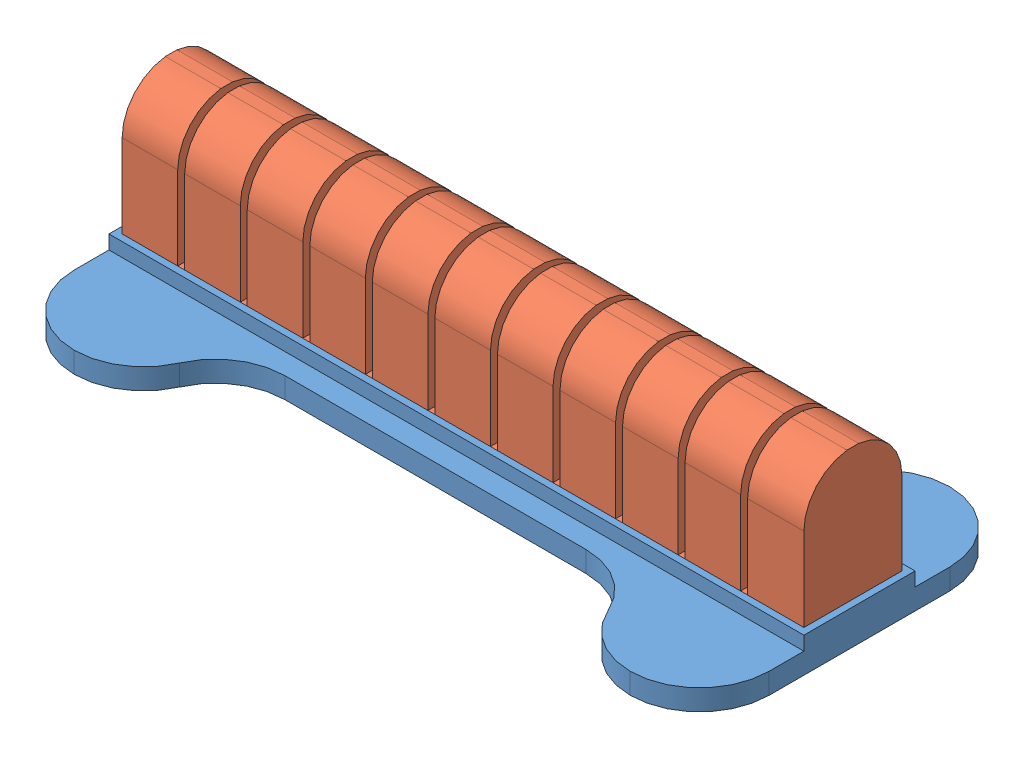
SolidWorks assembly Assem_nov4, configuration Default. Lengths in mm.
Overall size (100 24 46).
3 component instances, 3 part files, 6 mates.
Components (placement in the parent):
- SR_nov4_Male-1: SR_nov4_Male [Default] at (-87.585 -18.8498 34.1852) size (100 19 46)
- FInger_actuator_nov4-1: FInger_actuator_nov4 [Default] at (-87.585 -13.8498 18.1852) size (98.1 22 14.1)
- SR_Oct31_female-1: SR_Oct31_female [Default] at (187.4738 6.1502 -77.3442) x (1 0 0) z (0 0 -1) size (104 22 46) (hidden)
Mates (geometry in assembly coordinates):
- Coincident1: coincident: plane of SR_nov4_Male-1 through (-87.585 -13.8498 34.1852) normal (0 1 0); plane of FInger_actuator_nov4-1 through (-87.585 -13.8498 18.1852) normal (0 -1 0)
- Coincident2: coincident: plane of SR_nov4_Male-1 through (-87.585 -15.8498 34.1852) normal (-1 0 0); plane of FInger_actuator_nov4-1 through (-87.585 5.1502 18.1852) normal (-1 0 0)
- Coincident3: coincident: plane of SR_nov4_Male-1 through (-87.585 -12.8498 34.1852) normal (0 0 1); plane of FInger_actuator_nov4-1 through (-87.585 5.1502 34.1852) normal (0 0 1)
- Coincident9: coincident: plane of SR_nov4_Male-1 through (-87.585 -15.8498 34.1852) normal (-1 0 0); plane of SR_Oct31_female-1 through (-87.585 -13.8498 34.1852) normal (-1 0 0)
- Coincident10: coincident: plane of SR_nov4_Male-1 through (-87.585 -12.8498 18.1852) normal (0 0 -1); plane of SR_Oct31_female-1 through (-87.585 -13.8498 18.1852) normal (0 0 -1)
- Coincident11: coincident: plane of SR_nov4_Male-1 through (-87.585 -13.8498 34.1852) normal (0 1 0); plane of SR_Oct31_female-1 through (187.4738 -13.8498 -77.3442) normal (0 -1 0)
